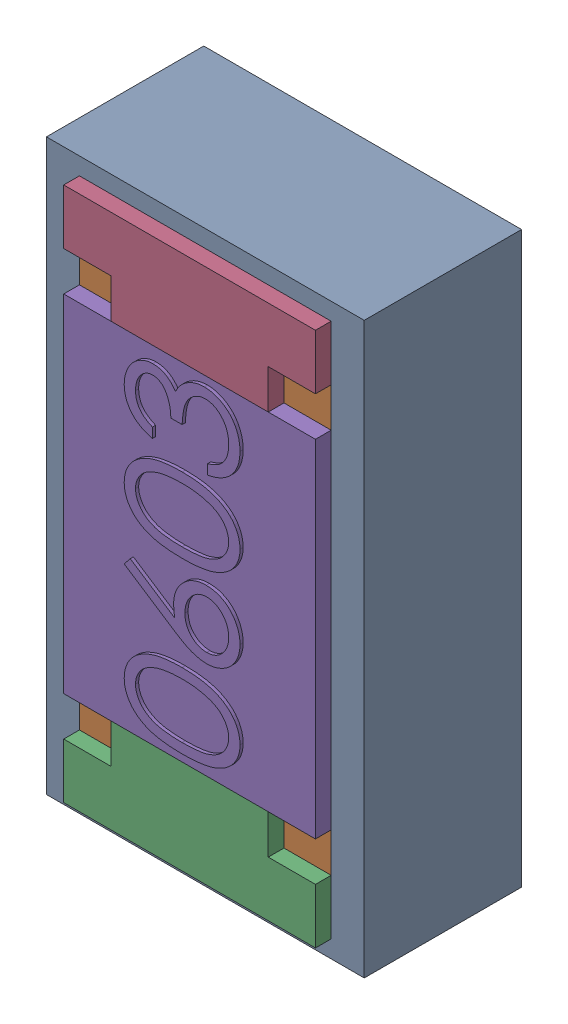
SolidWorks assembly SB15, configuration Default. Lengths in mm.
Overall size (1.01 1.81 0.56).
3 component instances, 2 part files, 0 mates.
Components (placement in the parent):
- 1088884704-1: 1088884704 [Default] at (15.2 5.875 0) size (1.01 1.81 0.5)
  - Extruded-0-1: Extruded-0 [Default] at origin size (1.01 1.81 0.5)
- R0603-1: R0603 [Default] at (15.1999 5.8751 0) x (0 1 0) z (1 0 0) size (1.7 0.56 0.8)
